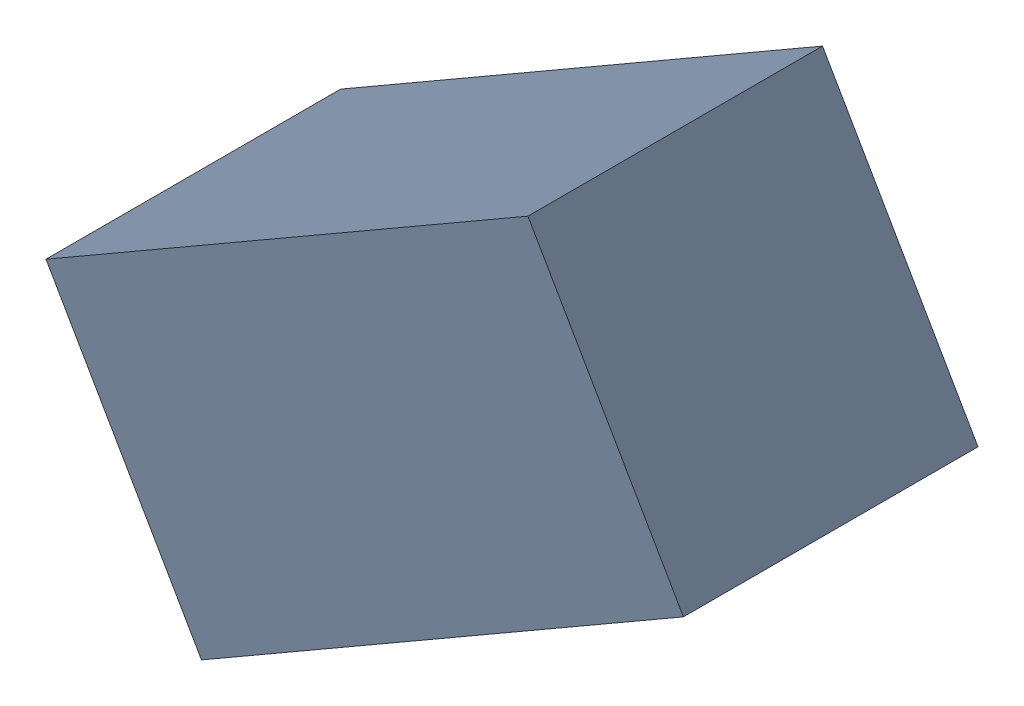
SolidWorks assembly R3_TDA5, configuration Standard. Lengths in mm.
Overall size (1.95 1.67 0.9).
2 component instances, 1 part files, 0 mates.
Components (placement in the parent):
- 885544008-1: 885544008 [Standard] at (-47.2285 -24.6736 0) size (1.95 1.67 0.9)
  - Extruded_15-1: Extruded_15 [Standard] at origin size (1.95 1.67 0.9)
